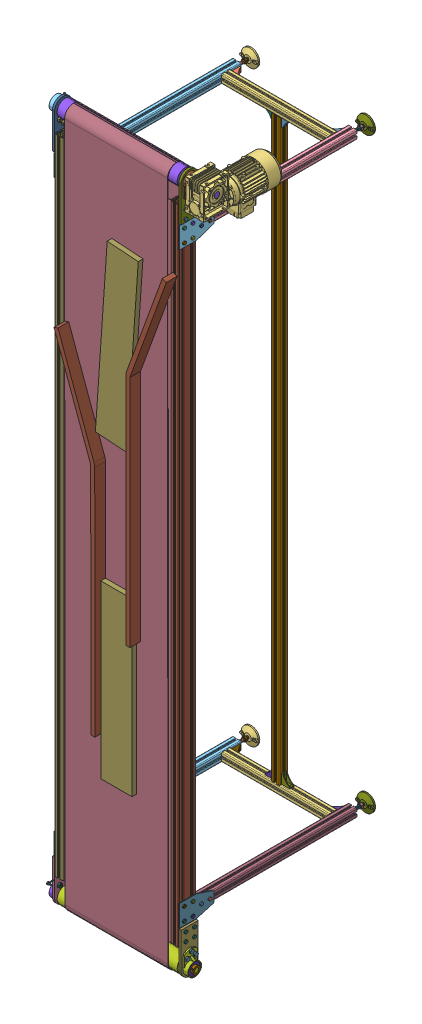
SolidWorks assembly conveyor_145x1200_complete, configuration Domyślna. Lengths in mm.
Overall size (1226.45 3281.47 952.3).
230 component instances, 193 part files, 10 mates.
Components (placement in the parent):
- Belt Conveyor.step-1: Belt Conveyor.step [Domyślna] at (-64.4362 912.0124 3281.4657) size (783.77 3281.47 920.11)
  - 8260K11_Mounted Bearing with Three-Bolt Flange.step-1: 8260K11_Mounted Bearing with Three-Bolt Flange.step [Domyślna] at (341.4816 -2455.8636 499.638) x (0 0.005965 0.999982) z (1 0 0) size (100.43 3260.49 665.09)
    - 8260K11_Mounted Bearing with Three-Bolt Flange(Mirror) (3).step-1: 8260K11_Mounted Bearing with Three-Bolt Flange(Mirror) (3).step [Domyślna] at (0 0 -596.825) size (80.98 205.46 51.19)
      - Nut(Mirror) (1).step-1: Nut(Mirror) (1).step [Domyślna] at (0 -65.0875 12.4125) x (-1 0 0) z (0 0 1) size (19.64 19.63 31.4)
      - Nut(Mirror) (1).step-2: Nut(Mirror) (1).step [Domyślna] at (-19 -43.0875 12.4125) x (-1 0 0) z (0 0 1) size (19.64 19.63 31.4)
      - Nut(Mirror) (1).step-3: Nut(Mirror) (1).step [Domyślna] at (19 -43.0875 12.4125) x (-1 0 0) z (0 0 1) size (19.64 19.63 31.4)
      - 4 Hex(Mirror).step-1: 4 Hex(Mirror).step [Domyślna] at (20.8958 -150.1006 3.7625) x (0 0 1) z (-1 0 0) size (21.31 55.25 53.25)
      - 8260K11_Mounted Bearing with Three-Bolt Flange(Mirror) (3)-0.step-1: 8260K11_Mounted Bearing with Three-Bolt Flange(Mirror) (3)-0.step [Domyślna] at origin size (60.74 60.74 12.3)
      - 8260K11_Mounted Bearing with Three-Bolt Flange(Mirror) (3)-1.step-1: 8260K11_Mounted Bearing with Three-Bolt Flange(Mirror) (3)-1.step [Domyślna] at origin size (53.56 53.56 0.76)
      - 8260K11_Mounted Bearing with Three-Bolt Flange(Mirror) (3)-2.step-1: 8260K11_Mounted Bearing with Three-Bolt Flange(Mirror) (3)-2.step [Domyślna] at origin size (50.9 50.9 0.76)
      - 8260K11_Mounted Bearing with Three-Bolt Flange(Mirror) (3)-3.step-1: 8260K11_Mounted Bearing with Three-Bolt Flange(Mirror) (3)-3.step [Domyślna] at origin size (12.3 12.3 12.3)
      - 8260K11_Mounted Bearing with Three-Bolt Flange(Mirror) (3)-4.step-1: 8260K11_Mounted Bearing with Three-Bolt Flange(Mirror) (3)-4.step [Domyślna] at origin size (12.3 12.3 12.3)
      - 8260K11_Mounted Bearing with Three-Bolt Flange(Mirror) (3)-5.step-1: 8260K11_Mounted Bearing with Three-Bolt Flange(Mirror) (3)-5.step [Domyślna] at origin size (12.3 12.3 12.3)
      - 8260K11_Mounted Bearing with Three-Bolt Flange(Mirror) (3)-6.step-1: 8260K11_Mounted Bearing with Three-Bolt Flange(Mirror) (3)-6.step [Domyślna] at origin size (12.3 12.3 12.3)
      - 8260K11_Mounted Bearing with Three-Bolt Flange(Mirror) (3)-7.step-1: 8260K11_Mounted Bearing with Three-Bolt Flange(Mirror) (3)-7.step [Domyślna] at origin size (12.3 12.3 12.3)
      - 8260K11_Mounted Bearing with Three-Bolt Flange(Mirror) (3)-8.step-1: 8260K11_Mounted Bearing with Three-Bolt Flange(Mirror) (3)-8.step [Domyślna] at origin size (12.3 12.3 12.3)
      - 8260K11_Mounted Bearing with Three-Bolt Flange(Mirror) (3)-9.step-1: 8260K11_Mounted Bearing with Three-Bolt Flange(Mirror) (3)-9.step [Domyślna] at origin size (66.58 109.49 25.4)
      - 8260K11_Mounted Bearing with Three-Bolt Flange(Mirror) (3)-10.step-1: 8260K11_Mounted Bearing with Three-Bolt Flange(Mirror) (3)-10.step [Domyślna] at origin size (13.07 13.07 9.52)
      - 8260K11_Mounted Bearing with Three-Bolt Flange(Mirror) (3)-11.step-1: 8260K11_Mounted Bearing with Three-Bolt Flange(Mirror) (3)-11.step [Domyślna] at origin size (33.87 33.87 32.54)
      - 8260K11_Mounted Bearing with Three-Bolt Flange(Mirror) (3)-12.step-1: 8260K11_Mounted Bearing with Three-Bolt Flange(Mirror) (3)-12.step [Domyślna] at origin size (6.25 7.12 6.25)
      - 8260K11_Mounted Bearing with Three-Bolt Flange(Mirror) (3)-13.step-1: 8260K11_Mounted Bearing with Three-Bolt Flange(Mirror) (3)-13.step [Domyślna] at origin size (8.65 8.34 6.25)
      - 8260K11_Mounted Bearing with Three-Bolt Flange(Mirror) (3)-14.step-1: 8260K11_Mounted Bearing with Three-Bolt Flange(Mirror) (3)-14.step [Domyślna] at origin size (80.98 205.46 10)
    - 8260K11_Mounted Bearing with Three-Bolt Flange(Mirror) (4).step-1: 8260K11_Mounted Bearing with Three-Bolt Flange(Mirror) (4).step [Domyślna] at (18.9701 -3180.0156 0) x (0.999929 0.01193 0) z (0 0 -1) size (80.98 205.46 51.19)
      - Nut(Mirror) (2).step-1: Nut(Mirror) (2).step [Domyślna] at (0 -65.0875 12.4125) x (-1 0 0) z (0 0 1) size (19.64 19.63 31.4)
      - Nut(Mirror) (2).step-2: Nut(Mirror) (2).step [Domyślna] at (-19 -43.0875 12.4125) x (-1 0 0) z (0 0 1) size (19.64 19.63 31.4)
      - Nut(Mirror) (2).step-3: Nut(Mirror) (2).step [Domyślna] at (19 -43.0875 12.4125) x (-1 0 0) z (0 0 1) size (19.64 19.63 31.4)
      - 4 Hex(Mirror) (1).step-1: 4 Hex(Mirror) (1).step [Domyślna] at (20.8958 -150.1006 3.7625) x (0 0 1) z (-1 0 0) size (21.31 55.25 53.25)
      - 8260K11_Mounted Bearing with Three-Bolt Flange(Mirror) (4)-15.step-1: 8260K11_Mounted Bearing with Three-Bolt Flange(Mirror) (4)-15.step [Domyślna] at origin size (60.74 60.74 12.3)
      - 8260K11_Mounted Bearing with Three-Bolt Flange(Mirror) (4)-16.step-1: 8260K11_Mounted Bearing with Three-Bolt Flange(Mirror) (4)-16.step [Domyślna] at origin size (53.56 53.56 0.76)
      - 8260K11_Mounted Bearing with Three-Bolt Flange(Mirror) (4)-17.step-1: 8260K11_Mounted Bearing with Three-Bolt Flange(Mirror) (4)-17.step [Domyślna] at origin size (50.9 50.9 0.76)
      - 8260K11_Mounted Bearing with Three-Bolt Flange(Mirror) (4)-18.step-1: 8260K11_Mounted Bearing with Three-Bolt Flange(Mirror) (4)-18.step [Domyślna] at origin size (12.3 12.3 12.3)
      - 8260K11_Mounted Bearing with Three-Bolt Flange(Mirror) (4)-19.step-1: 8260K11_Mounted Bearing with Three-Bolt Flange(Mirror) (4)-19.step [Domyślna] at origin size (12.3 12.3 12.3)
      - 8260K11_Mounted Bearing with Three-Bolt Flange(Mirror) (4)-20.step-1: 8260K11_Mounted Bearing with Three-Bolt Flange(Mirror) (4)-20.step [Domyślna] at origin size (12.3 12.3 12.3)
      - 8260K11_Mounted Bearing with Three-Bolt Flange(Mirror) (4)-21.step-1: 8260K11_Mounted Bearing with Three-Bolt Flange(Mirror) (4)-21.step [Domyślna] at origin size (12.3 12.3 12.3)
      - 8260K11_Mounted Bearing with Three-Bolt Flange(Mirror) (4)-22.step-1: 8260K11_Mounted Bearing with Three-Bolt Flange(Mirror) (4)-22.step [Domyślna] at origin size (12.3 12.3 12.3)
      - 8260K11_Mounted Bearing with Three-Bolt Flange(Mirror) (4)-23.step-1: 8260K11_Mounted Bearing with Three-Bolt Flange(Mirror) (4)-23.step [Domyślna] at origin size (12.3 12.3 12.3)
      - 8260K11_Mounted Bearing with Three-Bolt Flange(Mirror) (4)-24.step-1: 8260K11_Mounted Bearing with Three-Bolt Flange(Mirror) (4)-24.step [Domyślna] at origin size (66.58 109.49 25.4)
      - 8260K11_Mounted Bearing with Three-Bolt Flange(Mirror) (4)-25.step-1: 8260K11_Mounted Bearing with Three-Bolt Flange(Mirror) (4)-25.step [Domyślna] at origin size (13.07 13.07 9.52)
      - 8260K11_Mounted Bearing with Three-Bolt Flange(Mirror) (4)-26.step-1: 8260K11_Mounted Bearing with Three-Bolt Flange(Mirror) (4)-26.step [Domyślna] at origin size (33.87 33.87 32.54)
      - 8260K11_Mounted Bearing with Three-Bolt Flange(Mirror) (4)-27.step-1: 8260K11_Mounted Bearing with Three-Bolt Flange(Mirror) (4)-27.step [Domyślna] at origin size (6.25 7.12 6.25)
      - 8260K11_Mounted Bearing with Three-Bolt Flange(Mirror) (4)-28.step-1: 8260K11_Mounted Bearing with Three-Bolt Flange(Mirror) (4)-28.step [Domyślna] at origin size (8.65 8.34 6.25)
      - 8260K11_Mounted Bearing with Three-Bolt Flange(Mirror) (4)-29.step-1: 8260K11_Mounted Bearing with Three-Bolt Flange(Mirror) (4)-29.step [Domyślna] at origin size (80.98 205.46 10)
    - 8260K11_Mounted Bearing with Three-Bolt Flange(Mirror) (5).step-1: 8260K11_Mounted Bearing with Three-Bolt Flange(Mirror) (5).step [Domyślna] at (0 0 -596.825) size (100.43 3260.49 665.09)
      - 8260K11_Mounted Bearing with Three-Bolt Flange(Mirror) (3)(Mirror) (1).step-1: 8260K11_Mounted Bearing with Three-Bolt Flange(Mirror) (3)(Mirror) (1).step [Domyślna] at (0 0 596.825) size (80.98 205.46 51.19)
        - Nut(Mirror) (1)(Mirror) (1).step-1: Nut(Mirror) (1)(Mirror) (1).step [Domyślna] at (0 -65.0875 -12.4125) x (-1 0 0) z (0 0 1) size (19.64 19.63 31.4)
        - Nut(Mirror) (1)(Mirror) (1).step-2: Nut(Mirror) (1)(Mirror) (1).step [Domyślna] at (-19 -43.0875 -12.4125) x (-1 0 0) z (0 0 1) size (19.64 19.63 31.4)
        - Nut(Mirror) (1)(Mirror) (1).step-3: Nut(Mirror) (1)(Mirror) (1).step [Domyślna] at (19 -43.0875 -12.4125) x (-1 0 0) z (0 0 1) size (19.64 19.63 31.4)
        - 4 Hex(Mirror)(Mirror) (1).step-1: 4 Hex(Mirror)(Mirror) (1).step [Domyślna] at (20.8958 -150.1006 -3.7625) x (0 0 -1) z (1 0 0) size (21.31 55.25 55.26)
        - 8260K11_Mounted Bearing with Three-Bolt Flange(Mirror) (3)(Mirror) (1)-30.step-1: 8260K11_Mounted Bearing with Three-Bolt Flange(Mirror) (3)(Mirror) (1)-30.step [Domyślna] at origin size (60.74 60.74 12.3)
        - 8260K11_Mounted Bearing with Three-Bolt Flange(Mirror) (3)(Mirror) (1)-31.step-1: 8260K11_Mounted Bearing with Three-Bolt Flange(Mirror) (3)(Mirror) (1)-31.step [Domyślna] at origin size (53.56 53.56 0.76)
        - 8260K11_Mounted Bearing with Three-Bolt Flange(Mirror) (3)(Mirror) (1)-32.step-1: 8260K11_Mounted Bearing with Three-Bolt Flange(Mirror) (3)(Mirror) (1)-32.step [Domyślna] at origin size (50.9 50.9 0.76)
        - 8260K11_Mounted Bearing with Three-Bolt Flange(Mirror) (3)(Mirror) (1)-33.step-1: 8260K11_Mounted Bearing with Three-Bolt Flange(Mirror) (3)(Mirror) (1)-33.step [Domyślna] at origin size (12.3 12.3 12.3)
        - 8260K11_Mounted Bearing with Three-Bolt Flange(Mirror) (3)(Mirror) (1)-34.step-1: 8260K11_Mounted Bearing with Three-Bolt Flange(Mirror) (3)(Mirror) (1)-34.step [Domyślna] at origin size (12.3 12.3 12.3)
        - 8260K11_Mounted Bearing with Three-Bolt Flange(Mirror) (3)(Mirror) (1)-35.step-1: 8260K11_Mounted Bearing with Three-Bolt Flange(Mirror) (3)(Mirror) (1)-35.step [Domyślna] at origin size (12.3 12.3 12.3)
        - 8260K11_Mounted Bearing with Three-Bolt Flange(Mirror) (3)(Mirror) (1)-36.step-1: 8260K11_Mounted Bearing with Three-Bolt Flange(Mirror) (3)(Mirror) (1)-36.step [Domyślna] at origin size (12.3 12.3 12.3)
        - 8260K11_Mounted Bearing with Three-Bolt Flange(Mirror) (3)(Mirror) (1)-37.step-1: 8260K11_Mounted Bearing with Three-Bolt Flange(Mirror) (3)(Mirror) (1)-37.step [Domyślna] at origin size (12.3 12.3 12.3)
        - 8260K11_Mounted Bearing with Three-Bolt Flange(Mirror) (3)(Mirror) (1)-38.step-1: 8260K11_Mounted Bearing with Three-Bolt Flange(Mirror) (3)(Mirror) (1)-38.step [Domyślna] at origin size (12.3 12.3 12.3)
        - 8260K11_Mounted Bearing with Three-Bolt Flange(Mirror) (3)(Mirror) (1)-39.step-1: 8260K11_Mounted Bearing with Three-Bolt Flange(Mirror) (3)(Mirror) (1)-39.step [Domyślna] at origin size (66.58 109.49 25.4)
        - 8260K11_Mounted Bearing with Three-Bolt Flange(Mirror) (3)(Mirror) (1)-40.step-1: 8260K11_Mounted Bearing with Three-Bolt Flange(Mirror) (3)(Mirror) (1)-40.step [Domyślna] at origin size (13.07 13.07 9.52)
        - 8260K11_Mounted Bearing with Three-Bolt Flange(Mirror) (3)(Mirror) (1)-41.step-1: 8260K11_Mounted Bearing with Three-Bolt Flange(Mirror) (3)(Mirror) (1)-41.step [Domyślna] at origin size (33.87 33.87 32.54)
        - 8260K11_Mounted Bearing with Three-Bolt Flange(Mirror) (3)(Mirror) (1)-42.step-1: 8260K11_Mounted Bearing with Three-Bolt Flange(Mirror) (3)(Mirror) (1)-42.step [Domyślna] at origin size (6.25 7.12 6.25)
        - 8260K11_Mounted Bearing with Three-Bolt Flange(Mirror) (3)(Mirror) (1)-43.step-1: 8260K11_Mounted Bearing with Three-Bolt Flange(Mirror) (3)(Mirror) (1)-43.step [Domyślna] at origin size (8.65 8.34 6.25)
        - 8260K11_Mounted Bearing with Three-Bolt Flange(Mirror) (3)(Mirror) (1)-44.step-1: 8260K11_Mounted Bearing with Three-Bolt Flange(Mirror) (3)(Mirror) (1)-44.step [Domyślna] at origin size (80.98 205.46 10)
      - 8260K11_Mounted Bearing with Three-Bolt Flange(Mirror) (4)(Mirror).step-1: 8260K11_Mounted Bearing with Three-Bolt Flange(Mirror) (4)(Mirror).step [Domyślna] at (18.9701 -3180.0156 0) x (0.999929 0.01193 0) z (0 0 -1) size (80.98 205.46 51.19)
        - Nut(Mirror) (2)(Mirror).step-1: Nut(Mirror) (2)(Mirror).step [Domyślna] at (0 -65.0875 -12.4125) x (-1 0 0) z (0 0 1) size (19.64 19.63 31.4)
        - Nut(Mirror) (2)(Mirror).step-2: Nut(Mirror) (2)(Mirror).step [Domyślna] at (-19 -43.0875 -12.4125) x (-1 0 0) z (0 0 1) size (19.64 19.63 31.4)
        - Nut(Mirror) (2)(Mirror).step-3: Nut(Mirror) (2)(Mirror).step [Domyślna] at (19 -43.0875 -12.4125) x (-1 0 0) z (0 0 1) size (19.64 19.63 31.4)
        - 4 Hex(Mirror) (1)(Mirror).step-1: 4 Hex(Mirror) (1)(Mirror).step [Domyślna] at (20.8958 -150.1006 -3.7625) x (0 0 -1) z (1 0 0) size (21.31 55.25 55.26)
        - 8260K11_Mounted Bearing with Three-Bolt Flange(Mirror) (4)(Mirror)-45.step-1: 8260K11_Mounted Bearing with Three-Bolt Flange(Mirror) (4)(Mirror)-45.step [Domyślna] at origin size (60.74 60.74 12.3)
        - 8260K11_Mounted Bearing with Three-Bolt Flange(Mirror) (4)(Mirror)-46.step-1: 8260K11_Mounted Bearing with Three-Bolt Flange(Mirror) (4)(Mirror)-46.step [Domyślna] at origin size (53.56 53.56 0.76)
        - 8260K11_Mounted Bearing with Three-Bolt Flange(Mirror) (4)(Mirror)-47.step-1: 8260K11_Mounted Bearing with Three-Bolt Flange(Mirror) (4)(Mirror)-47.step [Domyślna] at origin size (50.9 50.9 0.76)
        - 8260K11_Mounted Bearing with Three-Bolt Flange(Mirror) (4)(Mirror)-48.step-1: 8260K11_Mounted Bearing with Three-Bolt Flange(Mirror) (4)(Mirror)-48.step [Domyślna] at origin size (12.3 12.3 12.3)
        - 8260K11_Mounted Bearing with Three-Bolt Flange(Mirror) (4)(Mirror)-49.step-1: 8260K11_Mounted Bearing with Three-Bolt Flange(Mirror) (4)(Mirror)-49.step [Domyślna] at origin size (12.3 12.3 12.3)
        - 8260K11_Mounted Bearing with Three-Bolt Flange(Mirror) (4)(Mirror)-50.step-1: 8260K11_Mounted Bearing with Three-Bolt Flange(Mirror) (4)(Mirror)-50.step [Domyślna] at origin size (12.3 12.3 12.3)
        - 8260K11_Mounted Bearing with Three-Bolt Flange(Mirror) (4)(Mirror)-51.step-1: 8260K11_Mounted Bearing with Three-Bolt Flange(Mirror) (4)(Mirror)-51.step [Domyślna] at origin size (12.3 12.3 12.3)
        - 8260K11_Mounted Bearing with Three-Bolt Flange(Mirror) (4)(Mirror)-52.step-1: 8260K11_Mounted Bearing with Three-Bolt Flange(Mirror) (4)(Mirror)-52.step [Domyślna] at origin size (12.3 12.3 12.3)
        - 8260K11_Mounted Bearing with Three-Bolt Flange(Mirror) (4)(Mirror)-53.step-1: 8260K11_Mounted Bearing with Three-Bolt Flange(Mirror) (4)(Mirror)-53.step [Domyślna] at origin size (12.3 12.3 12.3)
        - 8260K11_Mounted Bearing with Three-Bolt Flange(Mirror) (4)(Mirror)-54.step-1: 8260K11_Mounted Bearing with Three-Bolt Flange(Mirror) (4)(Mirror)-54.step [Domyślna] at origin size (66.58 109.49 25.4)
        - 8260K11_Mounted Bearing with Three-Bolt Flange(Mirror) (4)(Mirror)-55.step-1: 8260K11_Mounted Bearing with Three-Bolt Flange(Mirror) (4)(Mirror)-55.step [Domyślna] at origin size (13.07 13.07 9.52)
        - 8260K11_Mounted Bearing with Three-Bolt Flange(Mirror) (4)(Mirror)-56.step-1: 8260K11_Mounted Bearing with Three-Bolt Flange(Mirror) (4)(Mirror)-56.step [Domyślna] at origin size (33.87 33.87 32.54)
        - 8260K11_Mounted Bearing with Three-Bolt Flange(Mirror) (4)(Mirror)-57.step-1: 8260K11_Mounted Bearing with Three-Bolt Flange(Mirror) (4)(Mirror)-57.step [Domyślna] at origin size (6.25 7.12 6.25)
        - 8260K11_Mounted Bearing with Three-Bolt Flange(Mirror) (4)(Mirror)-58.step-1: 8260K11_Mounted Bearing with Three-Bolt Flange(Mirror) (4)(Mirror)-58.step [Domyślna] at origin size (8.65 8.34 6.25)
        - 8260K11_Mounted Bearing with Three-Bolt Flange(Mirror) (4)(Mirror)-59.step-1: 8260K11_Mounted Bearing with Three-Bolt Flange(Mirror) (4)(Mirror)-59.step [Domyślna] at origin size (80.98 205.46 10)
      - Nut(Mirror) (3).step-1: Nut(Mirror) (3).step [Domyślna] at (0 -65.0875 12.4125) x (-1 0 0) z (0 0 1) size (19.64 19.63 31.4)
      - Nut(Mirror) (3).step-2: Nut(Mirror) (3).step [Domyślna] at (-19 -43.0875 12.4125) x (-1 0 0) z (0 0 1) size (19.64 19.63 31.4)
      - Nut(Mirror) (3).step-3: Nut(Mirror) (3).step [Domyślna] at (19 -43.0875 12.4125) x (-1 0 0) z (0 0 1) size (19.64 19.63 31.4)
      - 4 Hex(Mirror) (2).step-1: 4 Hex(Mirror) (2).step [Domyślna] at (20.8958 -150.1006 3.7625) x (0 0 1) z (-1 0 0) size (21.31 55.25 53.25)
      - 8260K11_Mounted Bearing with Three-Bolt Flange(Mirror) (5)-60.step-1: 8260K11_Mounted Bearing with Three-Bolt Flange(Mirror) (5)-60.step [Domyślna] at origin size (60.74 60.74 12.3)
      - 8260K11_Mounted Bearing with Three-Bolt Flange(Mirror) (5)-61.step-1: 8260K11_Mounted Bearing with Three-Bolt Flange(Mirror) (5)-61.step [Domyślna] at origin size (53.56 53.56 0.76)
      - 8260K11_Mounted Bearing with Three-Bolt Flange(Mirror) (5)-62.step-1: 8260K11_Mounted Bearing with Three-Bolt Flange(Mirror) (5)-62.step [Domyślna] at origin size (50.9 50.9 0.76)
      - 8260K11_Mounted Bearing with Three-Bolt Flange(Mirror) (5)-63.step-1: 8260K11_Mounted Bearing with Three-Bolt Flange(Mirror) (5)-63.step [Domyślna] at origin size (12.3 12.3 12.3)
      - 8260K11_Mounted Bearing with Three-Bolt Flange(Mirror) (5)-64.step-1: 8260K11_Mounted Bearing with Three-Bolt Flange(Mirror) (5)-64.step [Domyślna] at origin size (12.3 12.3 12.3)
      - 8260K11_Mounted Bearing with Three-Bolt Flange(Mirror) (5)-65.step-1: 8260K11_Mounted Bearing with Three-Bolt Flange(Mirror) (5)-65.step [Domyślna] at origin size (12.3 12.3 12.3)
      - 8260K11_Mounted Bearing with Three-Bolt Flange(Mirror) (5)-66.step-1: 8260K11_Mounted Bearing with Three-Bolt Flange(Mirror) (5)-66.step [Domyślna] at origin size (12.3 12.3 12.3)
      - 8260K11_Mounted Bearing with Three-Bolt Flange(Mirror) (5)-67.step-1: 8260K11_Mounted Bearing with Three-Bolt Flange(Mirror) (5)-67.step [Domyślna] at origin size (12.3 12.3 12.3)
      - 8260K11_Mounted Bearing with Three-Bolt Flange(Mirror) (5)-68.step-1: 8260K11_Mounted Bearing with Three-Bolt Flange(Mirror) (5)-68.step [Domyślna] at origin size (12.3 12.3 12.3)
      - 8260K11_Mounted Bearing with Three-Bolt Flange(Mirror) (5)-69.step-1: 8260K11_Mounted Bearing with Three-Bolt Flange(Mirror) (5)-69.step [Domyślna] at origin size (66.58 109.49 25.4)
      - 8260K11_Mounted Bearing with Three-Bolt Flange(Mirror) (5)-70.step-1: 8260K11_Mounted Bearing with Three-Bolt Flange(Mirror) (5)-70.step [Domyślna] at origin size (13.07 13.07 9.52)
      - 8260K11_Mounted Bearing with Three-Bolt Flange(Mirror) (5)-71.step-1: 8260K11_Mounted Bearing with Three-Bolt Flange(Mirror) (5)-71.step [Domyślna] at origin size (33.87 33.87 32.54)
      - 8260K11_Mounted Bearing with Three-Bolt Flange(Mirror) (5)-72.step-1: 8260K11_Mounted Bearing with Three-Bolt Flange(Mirror) (5)-72.step [Domyślna] at origin size (6.25 7.12 6.25)
      - 8260K11_Mounted Bearing with Three-Bolt Flange(Mirror) (5)-73.step-1: 8260K11_Mounted Bearing with Three-Bolt Flange(Mirror) (5)-73.step [Domyślna] at origin size (8.65 8.34 6.25)
      - 8260K11_Mounted Bearing with Three-Bolt Flange(Mirror) (5)-74.step-1: 8260K11_Mounted Bearing with Three-Bolt Flange(Mirror) (5)-74.step [Domyślna] at origin size (80.98 205.46 10)
    - Nut.step-1: Nut.step [Domyślna] at (0 -65.0875 -12.4125) x (-1 0 0) z (0 0 1) size (19.64 19.63 31.4)
    - Nut.step-2: Nut.step [Domyślna] at (-19 -43.0875 -12.4125) x (-1 0 0) z (0 0 1) size (19.64 19.63 31.4)
    - Nut.step-3: Nut.step [Domyślna] at (19 -43.0875 -12.4125) x (-1 0 0) z (0 0 1) size (19.64 19.63 31.4)
    - 4 Hex.step-1: 4 Hex.step [Domyślna] at (20.8958 -150.1006 -3.7625) x (0 0 -1) z (1 0 0) size (21.31 55.25 55.26)
    - 8260K11_Mounted Bearing with Three-Bolt Flange-75.step-1: 8260K11_Mounted Bearing with Three-Bolt Flange-75.step [Domyślna] at origin size (60.74 60.74 12.3)
    - 8260K11_Mounted Bearing with Three-Bolt Flange-76.step-1: 8260K11_Mounted Bearing with Three-Bolt Flange-76.step [Domyślna] at origin size (53.56 53.56 0.76)
    - 8260K11_Mounted Bearing with Three-Bolt Flange-77.step-1: 8260K11_Mounted Bearing with Three-Bolt Flange-77.step [Domyślna] at origin size (50.9 50.9 0.76)
    - 8260K11_Mounted Bearing with Three-Bolt Flange-78.step-1: 8260K11_Mounted Bearing with Three-Bolt Flange-78.step [Domyślna] at origin size (12.3 12.3 12.3)
    - 8260K11_Mounted Bearing with Three-Bolt Flange-79.step-1: 8260K11_Mounted Bearing with Three-Bolt Flange-79.step [Domyślna] at origin size (12.3 12.3 12.3)
    - 8260K11_Mounted Bearing with Three-Bolt Flange-80.step-1: 8260K11_Mounted Bearing with Three-Bolt Flange-80.step [Domyślna] at origin size (12.3 12.3 12.3)
    - 8260K11_Mounted Bearing with Three-Bolt Flange-81.step-1: 8260K11_Mounted Bearing with Three-Bolt Flange-81.step [Domyślna] at origin size (12.3 12.3 12.3)
    - 8260K11_Mounted Bearing with Three-Bolt Flange-82.step-1: 8260K11_Mounted Bearing with Three-Bolt Flange-82.step [Domyślna] at origin size (12.3 12.3 12.3)
    - 8260K11_Mounted Bearing with Three-Bolt Flange-83.step-1: 8260K11_Mounted Bearing with Three-Bolt Flange-83.step [Domyślna] at origin size (12.3 12.3 12.3)
    - 8260K11_Mounted Bearing with Three-Bolt Flange-84.step-1: 8260K11_Mounted Bearing with Three-Bolt Flange-84.step [Domyślna] at origin size (66.58 109.49 25.4)
    - 8260K11_Mounted Bearing with Three-Bolt Flange-85.step-1: 8260K11_Mounted Bearing with Three-Bolt Flange-85.step [Domyślna] at origin size (13.07 13.07 9.52)
    - 8260K11_Mounted Bearing with Three-Bolt Flange-86.step-1: 8260K11_Mounted Bearing with Three-Bolt Flange-86.step [Domyślna] at origin size (33.87 33.87 32.54)
    - 8260K11_Mounted Bearing with Three-Bolt Flange-87.step-1: 8260K11_Mounted Bearing with Three-Bolt Flange-87.step [Domyślna] at origin size (6.25 7.12 6.25)
    - 8260K11_Mounted Bearing with Three-Bolt Flange-88.step-1: 8260K11_Mounted Bearing with Three-Bolt Flange-88.step [Domyślna] at origin size (8.65 8.34 6.25)
    - 8260K11_Mounted Bearing with Three-Bolt Flange-89.step-1: 8260K11_Mounted Bearing with Three-Bolt Flange-89.step [Domyślna] at origin size (80.98 205.46 10)
  - Support 4040.step-1: Support 4040.step [Domyślna] at (115.0482 419.3064 -290) size (620.02 2840.38 899.14)
    - Foot Adjuster v7.step-1: Foot Adjuster v7.step [Domyślna] at (198.0208 74.9024 -27.5496) size (80.02 80 119.51)
      - 91828A420_18-8 Stainless Steel Hex Nut.step-1: 91828A420_18-8 Stainless Steel Hex Nut.step [Domyślna] at (0 9.9637 40.0496) size (19 21.94 10.01)
      - 91828A420_18-8 Stainless Steel Hex Nut.step-2: 91828A420_18-8 Stainless Steel Hex Nut.step [Domyślna] at (0 9.9637 -9.9504) size (19 21.94 10.01)
      - Foot Adjuster v7-90.step-1: Foot Adjuster v7-90.step [Domyślna] at origin size (15 15 12)
      - Foot Adjuster v7-91.step-1: Foot Adjuster v7-91.step [Domyślna] at origin size (11.93 11.93 100.02)
      - Foot Adjuster v7-92.step-1: Foot Adjuster v7-92.step [Domyślna] at origin size (80.02 80 16)
      - Foot Adjuster v7-93.step-1: Foot Adjuster v7-93.step [Domyślna] at origin size (70 70 4)
    - Support 4040(Mirror).step-1: Support 4040(Mirror).step [Domyślna] at (-143.9583 0 0) x (-1 0 0) z (0 0 -1) size (80.02 100 899.14)
      - Foot Adjuster v7(Mirror).step-1: Foot Adjuster v7(Mirror).step [Domyślna] at (198.0208 74.9024 27.5496) size (80.02 80 119.51)
        - 91828A420_18-8 Stainless Steel Hex Nut(Mirror).step-1: 91828A420_18-8 Stainless Steel Hex Nut(Mirror).step [Domyślna] at (0 9.9637 -40.0496) size (19 21.94 10.01)
        - 91828A420_18-8 Stainless Steel Hex Nut(Mirror).step-2: 91828A420_18-8 Stainless Steel Hex Nut(Mirror).step [Domyślna] at (0 9.9637 9.9504) size (19 21.94 10.01)
        - Foot Adjuster v7(Mirror)-94.step-1: Foot Adjuster v7(Mirror)-94.step [Domyślna] at origin size (15 15 12)
        - Foot Adjuster v7(Mirror)-95.step-1: Foot Adjuster v7(Mirror)-95.step [Domyślna] at origin size (11.93 11.93 100.02)
        - Foot Adjuster v7(Mirror)-96.step-1: Foot Adjuster v7(Mirror)-96.step [Domyślna] at origin size (80.02 80 16)
        - Foot Adjuster v7(Mirror)-97.step-1: Foot Adjuster v7(Mirror)-97.step [Domyślna] at origin size (70 70 4)
      - Support 4040(Mirror)-98.step-1: Support 4040(Mirror)-98.step [Domyślna] at origin size (40 40 750)
      - Support 4040(Mirror)-99.step-1: Support 4040(Mirror)-99.step [Domyślna] at origin size (3 100 160.2)
      - Support 4040(Mirror)-100.step-1: Support 4040(Mirror)-100.step [Domyślna] at origin size (15.31 15.06 15.06)
      - Support 4040(Mirror)-101.step-1: Support 4040(Mirror)-101.step [Domyślna] at origin size (15.31 15.06 15.06)
      - Support 4040(Mirror)-102.step-1: Support 4040(Mirror)-102.step [Domyślna] at origin size (15.31 15.06 15.06)
      - Support 4040(Mirror)-103.step-1: Support 4040(Mirror)-103.step [Domyślna] at origin size (15.31 15.06 15.06)
      - Support 4040(Mirror)-104.step-1: Support 4040(Mirror)-104.step [Domyślna] at origin size (15.31 15.06 15.06)
      - Support 4040(Mirror)-105.step-1: Support 4040(Mirror)-105.step [Domyślna] at origin size (15.31 15.06 15.06)
    - Support 4040(Mirror) (1).step-1: Support 4040(Mirror) (1).step [Domyślna] at (0 -2570.2679 0) x (1 0 0) z (0 0 -1) size (620.02 100 899.14)
      - Foot Adjuster v7(Mirror) (1).step-1: Foot Adjuster v7(Mirror) (1).step [Domyślna] at (198.0208 74.9024 27.5496) size (80.02 80 119.51)
        - 91828A420_18-8 Stainless Steel Hex Nut(Mirror) (1).step-1: 91828A420_18-8 Stainless Steel Hex Nut(Mirror) (1).step [Domyślna] at (0 9.9637 -40.0496) size (19 21.94 10.01)
        - 91828A420_18-8 Stainless Steel Hex Nut(Mirror) (1).step-2: 91828A420_18-8 Stainless Steel Hex Nut(Mirror) (1).step [Domyślna] at (0 9.9637 9.9504) size (19 21.94 10.01)
        - Foot Adjuster v7(Mirror) (1)-106.step-1: Foot Adjuster v7(Mirror) (1)-106.step [Domyślna] at origin size (15 15 12)
        - Foot Adjuster v7(Mirror) (1)-107.step-1: Foot Adjuster v7(Mirror) (1)-107.step [Domyślna] at origin size (11.93 11.93 100.02)
        - Foot Adjuster v7(Mirror) (1)-108.step-1: Foot Adjuster v7(Mirror) (1)-108.step [Domyślna] at origin size (80.02 80 16)
        - Foot Adjuster v7(Mirror) (1)-109.step-1: Foot Adjuster v7(Mirror) (1)-109.step [Domyślna] at origin size (70 70 4)
      - Support 4040(Mirror)(Mirror).step-1: Support 4040(Mirror)(Mirror).step [Domyślna] at (-143.9583 0 0) x (-1 0 0) z (0 0 -1) size (80.02 100 899.14)
        - Foot Adjuster v7(Mirror)(Mirror).step-1: Foot Adjuster v7(Mirror)(Mirror).step [Domyślna] at (198.0208 74.9024 -27.5496) size (80.02 80 119.51)
          - 91828A420_18-8 Stainless Steel Hex Nut(Mirror)(Mirror).step-1: 91828A420_18-8 Stainless Steel Hex Nut(Mirror)(Mirror).step [Domyślna] at (0 9.9637 40.0496) size (19 21.94 10.01)
          - 91828A420_18-8 Stainless Steel Hex Nut(Mirror)(Mirror).step-2: 91828A420_18-8 Stainless Steel Hex Nut(Mirror)(Mirror).step [Domyślna] at (0 9.9637 -9.9504) size (19 21.94 10.01)
          - Foot Adjuster v7(Mirror)(Mirror)-110.step-1: Foot Adjuster v7(Mirror)(Mirror)-110.step [Domyślna] at origin size (15 15 12)
          - Foot Adjuster v7(Mirror)(Mirror)-111.step-1: Foot Adjuster v7(Mirror)(Mirror)-111.step [Domyślna] at origin size (11.93 11.93 100.02)
          - Foot Adjuster v7(Mirror)(Mirror)-112.step-1: Foot Adjuster v7(Mirror)(Mirror)-112.step [Domyślna] at origin size (80.02 80 16)
          - Foot Adjuster v7(Mirror)(Mirror)-113.step-1: Foot Adjuster v7(Mirror)(Mirror)-113.step [Domyślna] at origin size (70 70 4)
        - Support 4040(Mirror)(Mirror)-114.step-1: Support 4040(Mirror)(Mirror)-114.step [Domyślna] at origin size (40 40 750)
        - Support 4040(Mirror)(Mirror)-115.step-1: Support 4040(Mirror)(Mirror)-115.step [Domyślna] at origin size (3 100 160.2)
        - Support 4040(Mirror)(Mirror)-116.step-1: Support 4040(Mirror)(Mirror)-116.step [Domyślna] at origin size (15.31 15.02 13.05)
        - Support 4040(Mirror)(Mirror)-117.step-1: Support 4040(Mirror)(Mirror)-117.step [Domyślna] at origin size (15.31 15.02 13.05)
        - Support 4040(Mirror)(Mirror)-118.step-1: Support 4040(Mirror)(Mirror)-118.step [Domyślna] at origin size (15.31 15.02 13.05)
        - Support 4040(Mirror)(Mirror)-119.step-1: Support 4040(Mirror)(Mirror)-119.step [Domyślna] at origin size (15.31 15.02 13.05)
        - Support 4040(Mirror)(Mirror)-120.step-1: Support 4040(Mirror)(Mirror)-120.step [Domyślna] at origin size (15.31 15.02 13.05)
        - Support 4040(Mirror)(Mirror)-121.step-1: Support 4040(Mirror)(Mirror)-121.step [Domyślna] at origin size (15.31 15.02 13.05)
      - Support 4040(Mirror) (1)-122.step-1: Support 4040(Mirror) (1)-122.step [Domyślna] at origin size (40 40 750)
      - Support 4040(Mirror) (1)-123.step-1: Support 4040(Mirror) (1)-123.step [Domyślna] at origin size (3 100 160.2)
      - Support 4040(Mirror) (1)-124.step-1: Support 4040(Mirror) (1)-124.step [Domyślna] at origin size (15.31 15.06 15.06)
      - Support 4040(Mirror) (1)-125.step-1: Support 4040(Mirror) (1)-125.step [Domyślna] at origin size (15.31 15.06 15.06)
      - Support 4040(Mirror) (1)-126.step-1: Support 4040(Mirror) (1)-126.step [Domyślna] at origin size (15.31 15.06 15.06)
      - Support 4040(Mirror) (1)-127.step-1: Support 4040(Mirror) (1)-127.step [Domyślna] at origin size (15.31 15.06 15.06)
      - Support 4040(Mirror) (1)-128.step-1: Support 4040(Mirror) (1)-128.step [Domyślna] at origin size (15.31 15.06 15.06)
      - Support 4040(Mirror) (1)-129.step-1: Support 4040(Mirror) (1)-129.step [Domyślna] at origin size (15.31 15.06 15.06)
    - Component91.step-1: Component91.step [Domyślna] at (-250.2384 -383.8055 -1334.1725) x (-1 0 0) z (0 1 0) size (500 40 2780)
    - Support 4040-130.step-1: Support 4040-130.step [Domyślna] at origin size (40 40 750)
    - Support 4040-131.step-1: Support 4040-131.step [Domyślna] at origin size (3 100 160.2)
    - Support 4040-132.step-1: Support 4040-132.step [Domyślna] at origin size (15.31 15.02 13.05)
    - Support 4040-133.step-1: Support 4040-133.step [Domyślna] at origin size (15.31 15.02 13.05)
    - Support 4040-134.step-1: Support 4040-134.step [Domyślna] at origin size (15.31 15.02 13.05)
    - Support 4040-135.step-1: Support 4040-135.step [Domyślna] at origin size (15.31 15.02 13.05)
    - Support 4040-136.step-1: Support 4040-136.step [Domyślna] at origin size (15.31 15.02 13.05)
    - Support 4040-137.step-1: Support 4040-137.step [Domyślna] at origin size (15.31 15.02 13.05)
  - 8260K11_Mounted Bearing with Three-Bolt Flange(Mirror) (3)(Mirror).step-1: 8260K11_Mounted Bearing with Three-Bolt Flange(Mirror) (3)(Mirror).step [Domyślna] at (-255.3434 724.2086 499.638) x (0 -0.005965 0.999982) z (-1 0 0) size (80.98 205.46 51.19)
    - Nut(Mirror) (1)(Mirror).step-1: Nut(Mirror) (1)(Mirror).step [Domyślna] at (0 -65.0875 -12.4125) x (-1 0 0) z (0 0 1) size (19.64 19.63 31.4)
    - Nut(Mirror) (1)(Mirror).step-2: Nut(Mirror) (1)(Mirror).step [Domyślna] at (-19 -43.0875 -12.4125) x (-1 0 0) z (0 0 1) size (19.64 19.63 31.4)
    - Nut(Mirror) (1)(Mirror).step-3: Nut(Mirror) (1)(Mirror).step [Domyślna] at (19 -43.0875 -12.4125) x (-1 0 0) z (0 0 1) size (19.64 19.63 31.4)
    - 4 Hex(Mirror)(Mirror).step-1: 4 Hex(Mirror)(Mirror).step [Domyślna] at (20.8958 -150.1006 -3.7625) x (0 0 -1) z (1 0 0) size (21.31 55.25 55.26)
    - 8260K11_Mounted Bearing with Three-Bolt Flange(Mirror) (3)(Mirror)-138.step-1: 8260K11_Mounted Bearing with Three-Bolt Flange(Mirror) (3)(Mirror)-138.step [Domyślna] at origin size (60.74 60.74 12.3)
    - 8260K11_Mounted Bearing with Three-Bolt Flange(Mirror) (3)(Mirror)-139.step-1: 8260K11_Mounted Bearing with Three-Bolt Flange(Mirror) (3)(Mirror)-139.step [Domyślna] at origin size (53.56 53.56 0.76)
    - 8260K11_Mounted Bearing with Three-Bolt Flange(Mirror) (3)(Mirror)-140.step-1: 8260K11_Mounted Bearing with Three-Bolt Flange(Mirror) (3)(Mirror)-140.step [Domyślna] at origin size (50.9 50.9 0.76)
    - 8260K11_Mounted Bearing with Three-Bolt Flange(Mirror) (3)(Mirror)-141.step-1: 8260K11_Mounted Bearing with Three-Bolt Flange(Mirror) (3)(Mirror)-141.step [Domyślna] at origin size (12.3 12.3 12.3)
    - 8260K11_Mounted Bearing with Three-Bolt Flange(Mirror) (3)(Mirror)-142.step-1: 8260K11_Mounted Bearing with Three-Bolt Flange(Mirror) (3)(Mirror)-142.step [Domyślna] at origin size (12.3 12.3 12.3)
    - 8260K11_Mounted Bearing with Three-Bolt Flange(Mirror) (3)(Mirror)-143.step-1: 8260K11_Mounted Bearing with Three-Bolt Flange(Mirror) (3)(Mirror)-143.step [Domyślna] at origin size (12.3 12.3 12.3)
    - 8260K11_Mounted Bearing with Three-Bolt Flange(Mirror) (3)(Mirror)-144.step-1: 8260K11_Mounted Bearing with Three-Bolt Flange(Mirror) (3)(Mirror)-144.step [Domyślna] at origin size (12.3 12.3 12.3)
    - 8260K11_Mounted Bearing with Three-Bolt Flange(Mirror) (3)(Mirror)-145.step-1: 8260K11_Mounted Bearing with Three-Bolt Flange(Mirror) (3)(Mirror)-145.step [Domyślna] at origin size (12.3 12.3 12.3)
    - 8260K11_Mounted Bearing with Three-Bolt Flange(Mirror) (3)(Mirror)-146.step-1: 8260K11_Mounted Bearing with Three-Bolt Flange(Mirror) (3)(Mirror)-146.step [Domyślna] at origin size (12.3 12.3 12.3)
    - 8260K11_Mounted Bearing with Three-Bolt Flange(Mirror) (3)(Mirror)-147.step-1: 8260K11_Mounted Bearing with Three-Bolt Flange(Mirror) (3)(Mirror)-147.step [Domyślna] at origin size (66.58 109.49 25.4)
    - 8260K11_Mounted Bearing with Three-Bolt Flange(Mirror) (3)(Mirror)-148.step-1: 8260K11_Mounted Bearing with Three-Bolt Flange(Mirror) (3)(Mirror)-148.step [Domyślna] at origin size (13.07 13.07 9.52)
    - 8260K11_Mounted Bearing with Three-Bolt Flange(Mirror) (3)(Mirror)-149.step-1: 8260K11_Mounted Bearing with Three-Bolt Flange(Mirror) (3)(Mirror)-149.step [Domyślna] at origin size (33.87 33.87 32.54)
    - 8260K11_Mounted Bearing with Three-Bolt Flange(Mirror) (3)(Mirror)-150.step-1: 8260K11_Mounted Bearing with Three-Bolt Flange(Mirror) (3)(Mirror)-150.step [Domyślna] at origin size (6.25 7.12 6.25)
    - 8260K11_Mounted Bearing with Three-Bolt Flange(Mirror) (3)(Mirror)-151.step-1: 8260K11_Mounted Bearing with Three-Bolt Flange(Mirror) (3)(Mirror)-151.step [Domyślna] at origin size (8.65 8.34 6.25)
    - 8260K11_Mounted Bearing with Three-Bolt Flange(Mirror) (3)(Mirror)-152.step-1: 8260K11_Mounted Bearing with Three-Bolt Flange(Mirror) (3)(Mirror)-152.step [Domyślna] at origin size (80.98 205.46 10)
  - Frame8080.step-1: Frame8080.step [Domyślna] at (178.8966 634.1725 813.0691) x (0 0 -1) z (0 -1 0) size (80 40 3000)
  - 8080 v1(Mirror).step-1: 8080 v1(Mirror).step [Domyślna] at (-92.7585 634.1725 813.0691) x (0 0 -1) z (0 1 0) size (80 40 3000)
  - Belt doang v4.step-1: Belt doang v4.step [Domyślna] at (240 0 0) size (480 3259.3 84.09)
  - Angle Bracket v1.step-1: Angle Bracket v1.step [Domyślna] at (54.0691 484.1725 -220) x (0 0 1) z (1 0 0) size (20 45.8 38.8)
  - Angle Bracket v1(Mirror) (1).step-1: Angle Bracket v1(Mirror) (1).step [Domyślna] at (32.0691 484.1725 -220) x (0 0 1) z (1 0 0) size (20 45.8 38.8)
  - Angle Bracket v1(Mirror) (2).step-1: Angle Bracket v1(Mirror) (2).step [Domyślna] at (54.0691 -2215.8275 -220) x (0 0 1) z (-1 0 0) size (20 45.8 38.8)
  - Angle Bracket v1(Mirror) (1)(Mirror).step-1: Angle Bracket v1(Mirror) (1)(Mirror).step [Domyślna] at (32.0691 -2215.8275 -220) x (0 0 1) z (-1 0 0) size (20 45.8 38.8)
  - Angle Bracket v1(Mirror) (1)(Mirror).step-2: Angle Bracket v1(Mirror) (1)(Mirror).step [Domyślna] at (302.0691 -2235.0775 -240) x (0 1 0) z (-1 0 0) size (20 45.8 38.8)
  - Angle Bracket v1(Mirror) (1)(Mirror)(Mirror).step-1: Angle Bracket v1(Mirror) (1)(Mirror)(Mirror).step [Domyślna] at (-215.9309 -2235.0775 -240) x (0 1 0) z (-1 0 0) size (20 45.8 38.8)
  - Angle Bracket v1(Mirror) (1)(Mirror)(Mirror) (1).step-1: Angle Bracket v1(Mirror) (1)(Mirror)(Mirror) (1).step [Domyślna] at (302.0691 503.4225 -240) x (0 -1 0) z (1 0 0) size (20 45.8 38.8)
  - Angle Bracket v1(Mirror) (1)(Mirror)(Mirror)(Mirror).step-1: Angle Bracket v1(Mirror) (1)(Mirror)(Mirror)(Mirror).step [Domyślna] at (-215.9309 503.4225 -240) x (0 -1 0) z (1 0 0) size (20 45.8 38.8)
  - Motor.step-1: Motor.step [Domyślna] at (907.3504 750.0663 528.9842) x (-1 0 0) z (0 0.005965 0.999982) size (139.37 222.5 348.5)
  - Belt Conv Alu - BU.step-1: Belt Conv Alu - BU.step [Domyślna] at origin size (500 3000 30)
  - Belt Conv Alu - BU-153.step-1: Belt Conv Alu - BU-153.step [Domyślna] at origin size (10 1 1)
  - Belt Conv Alu - BU-154.step-1: Belt Conv Alu - BU-154.step [Domyślna] at origin size (10 1 1)
  - Belt Conv Alu - BU-155.step-1: Belt Conv Alu - BU-155.step [Domyślna] at origin size (665 76 76)
  - Belt Conv Alu - BU-156.step-1: Belt Conv Alu - BU-156.step [Domyślna] at origin size (760 76 76)
  - Belt Conv Alu - BU-157.step-1: Belt Conv Alu - BU-157.step [Domyślna] at origin size (40 2700 40)
- FU-R67TZ-1: FU-R67TZ [Default] at (-303.4136 -1473.5631 3846.1036) size (16.81 11.5 30)
- Część191^conveyor_145x1200_complete-1: Część191^conveyor_145x1200_complete [Domyślna] at origin (virtual)
- prowadnica-1: prowadnica [Domyślna] at (168.3385 1026.6072 3824.116) x (-0.34202 -0.939692 -0.000577) z (0 -0.000614 1) size (1532.53 393.44 50)
- prowadnica-2: prowadnica [Domyślna] at (-166.4654 582.6325 3873.8435) x (0.34202 -0.939692 -0.000577) z (0 0.000614 -1) size (1532.53 393.44 50)
- trans-brd-leader-145x800-1: trans-brd-leader-145x800 [Default] at (-71.5635 -529.5775 3845.1609) x (0 -1 -0.000614) z (0 0.000614 -1) size (800 145 22)
- trans-brd-leader-145x800-2: trans-brd-leader-145x800 [Default] at (-68.6667 859.7026 3846.0136) x (-0.069756 -0.997564 -0.000612) z (0 0.000614 -1) size (800 145 22)
Mates (geometry in assembly coordinates):
- Wspólnie3: coincident anti-aligned: plane of Belt Conveyor.step-1/8260K11_Mounted Bearing with Three-Bolt Flange.step-1/8260K11_Mounted Bearing with Three-Bolt Flange(Mirror) (3).step-1/8260K11_Mounted Bearing with Three-Bolt Flange(Mirror) (3)-14.step-1 through (-311.3672 -1378.6233 3821.1036) normal (0 0 1); plane of FU-R67TZ-1 through (-316.8136 -1474.6641 3821.1036) normal (0 0 -1)
- Wspólnie5: coincident anti-aligned: plane of Belt Conveyor.step-1/Belt doang v4.step-1 through (218.6326 -1543.8403 3822.5384) normal (0 -0.000614 1); plane of prowadnica-1 through (168.3385 1026.6072 3824.116) normal (0 0.000614 -1)
- Wspólnie7: coincident anti-aligned: plane of Belt Conveyor.step-1/Belt doang v4.step-1 through (218.6326 -1543.8403 3822.5384) normal (0 -0.000614 1); plane of prowadnica-2 through (-166.4654 582.6632 3823.8435) normal (0 0.000614 -1)
- Wspólnie8: coincident anti-aligned: plane of Belt Conveyor.step-1/Belt doang v4.step-1 through (218.6326 -1543.8403 3822.5384) normal (0 -0.000614 1); plane of trans-brd-leader-145x800-1 through (73.4365 -129.5641 3823.4064) normal (0 0.000614 -1)
- Równolegle1: parallel aligned: line of Belt Conveyor.step-1/Belt doang v4.step-1 through (218.6326 1632.3847 3824.4878) axis (0 -1 -0.000614); line of trans-brd-leader-145x800-1 through (73.4365 -129.5776 3845.4064) axis (0 -1 -0.000614)
- Wspólnie10: coincident anti-aligned: plane of prowadnica-1 through (73.4365 795.0736 3873.9739) normal (-1 0 0); plane of trans-brd-leader-145x800-1 through (73.4365 -929.5639 3822.9154) normal (1 0 0)
- Wspólnie11: coincident anti-aligned: plane of prowadnica-2 through (-71.5635 351.1603 3823.7014) normal (1 0 0); plane of trans-brd-leader-145x800-1 through (-71.5635 -129.5641 3823.4064) normal (-1 0 0)
- Wspólnie12: coincident: line of Belt Conveyor.step-1/Belt doang v4.step-1 through (-261.3674 -1543.8403 3822.5384) axis (0 1 0.000614); point of prowadnica-2
- Wspólnie13: coincident anti-aligned: plane of Belt Conveyor.step-1/Belt doang v4.step-1 through (218.6326 -1543.8403 3822.5384) normal (0 -0.000614 1); plane of trans-brd-leader-145x800-2 through (103.8827 1248.6269 3824.2523) normal (0 0.000614 -1)
- Kąt1: planar angle = 0.069813 rad aligned: line of trans-brd-leader-145x800-2 through (103.8827 1248.6134 3846.2523) axis (-0.069756 -0.997564 -0.000612); line of prowadnica-1 through (73.4365 786.2879 3823.9685) axis (0 -1 -0.000614)
